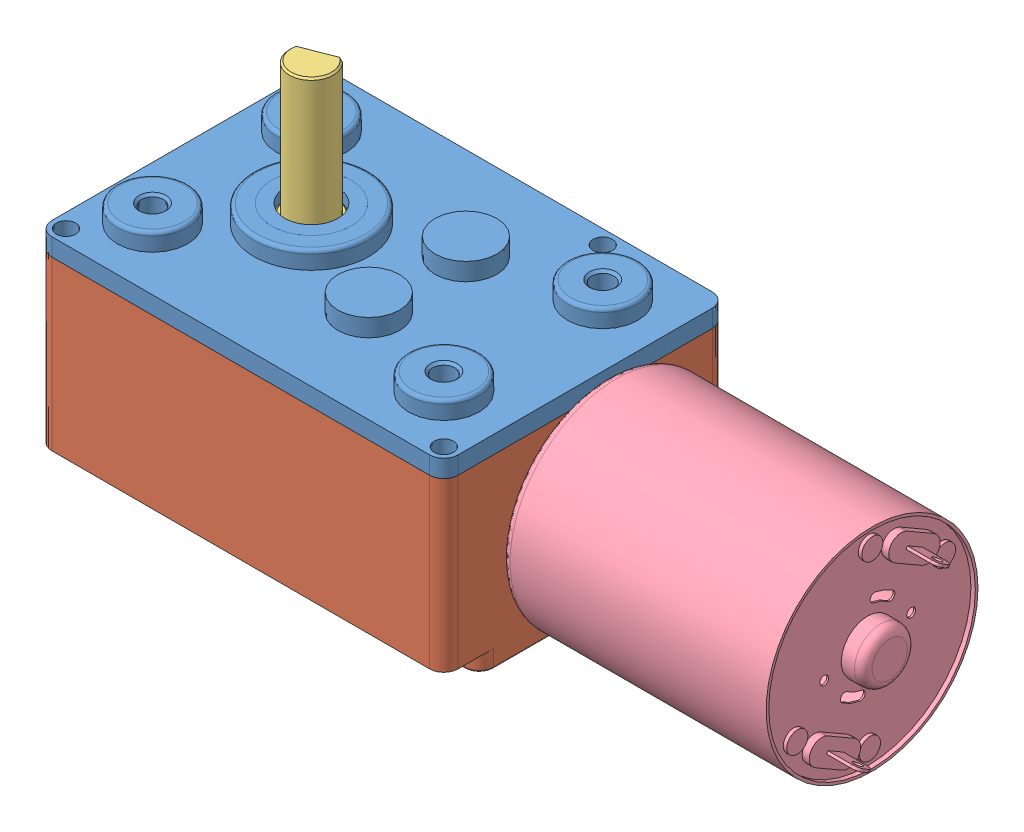
SolidWorks assembly TS-32GZ370-5300, configuration Default. Lengths in mm.
Overall size (79.8 40.5 32).
6 component instances, 5 part files, 9 mates.
Components (placement in the parent):
- TS-32GZ370-5300, COVER-1: TS-32GZ370-5300, COVER [Default] at origin size (46 21 32)
- TS-32GZ370-5300, GEAR BODY-1: TS-32GZ370-5300, GEAR BODY [Default] at (-1 0 0) size (46 21 32)
- TS-32GZ370-5300, SHAFT-1: TS-32GZ370-5300, SHAFT [Default] x (-0.366912 0 -0.930256) z (0.930256 0 -0.366912) size (6 28 6)
- TS-32GZ370-5300, DC MOTOR-1: TS-32GZ370-5300, DC MOTOR [Default] at (61 -10.5 -2.5) size (43.8 24 24) (flexible)
  - TS-32GZ370-5300, DC MOTOR BODY-1: TS-32GZ370-5300, DC MOTOR BODY [Default] at origin size (33.8 24 24)
  - TS-32GZ370-5300, DC MOTOR SHAFT-1: TS-32GZ370-5300, DC MOTOR SHAFT [Default] at (-20 0 0) x (1 0 0) z (0 0.450234 0.89291) size (40 2 2)
Mates (geometry in assembly coordinates):
- Coincident1: coordinate: point of TS-32GZ370-5300, COVER-1; point of assembly
- Coincident2: coincident anti-aligned: plane of TS-32GZ370-5300, COVER-1 through (0 0 0) normal (0 -1 0); plane of TS-32GZ370-5300, GEAR BODY-1 through (-1 0 0) normal (0 1 0)
- Concentric1: concentric aligned: cylinder of TS-32GZ370-5300, COVER-1 through (18.6 2 -14.4) axis (0 1 0) radius 1.1; cylinder of TS-32GZ370-5300, GEAR BODY-1 through (18.6 0 -14.4) axis (0 1 0) radius 0.8
- Concentric2: concentric aligned: cylinder of TS-32GZ370-5300, COVER-1 through (-13.4 2 14.4) axis (0 1 0) radius 1.1; cylinder of TS-32GZ370-5300, GEAR BODY-1 through (-13.4 0 14.4) axis (0 1 0) radius 0.8
- Coincident3: coincident aligned: plane of TS-32GZ370-5300, COVER-1 through (0 0 0) normal (0 1 0); plane of TS-32GZ370-5300, SHAFT-1 through (0 0 0) normal (0 1 0)
- Concentric3: concentric anti-aligned: cylinder of TS-32GZ370-5300, COVER-1 through (0 4 0) axis (0 -1 0) radius 3; cylinder of TS-32GZ370-5300, SHAFT-1 through (0 -10 0) axis (0 1 0) radius 3
- Concentric4: concentric anti-aligned: cylinder of TS-32GZ370-5300, GEAR BODY-1 through (-15 -10.5 -2.5) axis (1 0 0) radius 3; cylinder of TS-32GZ370-5300, DC MOTOR-1/TS-32GZ370-5300, DC MOTOR SHAFT-1 through (61 -10.5 -2.5) axis (-1 0 0) radius 1
- Coincident4: coincident anti-aligned: plane of TS-32GZ370-5300, GEAR BODY-1 through (31 -19 -16) normal (1 0 0); plane of TS-32GZ370-5300, DC MOTOR-1/TS-32GZ370-5300, DC MOTOR BODY-1 through (31 -10.5 -2.5) normal (-1 0 0)
- Parallel1: parallel aligned: plane of TS-32GZ370-5300, DC MOTOR-1/TS-32GZ370-5300, DC MOTOR BODY-1 through (61 -10.5 -2.5) normal (0 0 1); plane of assembly through (0 0 0) normal (0 0 1)
